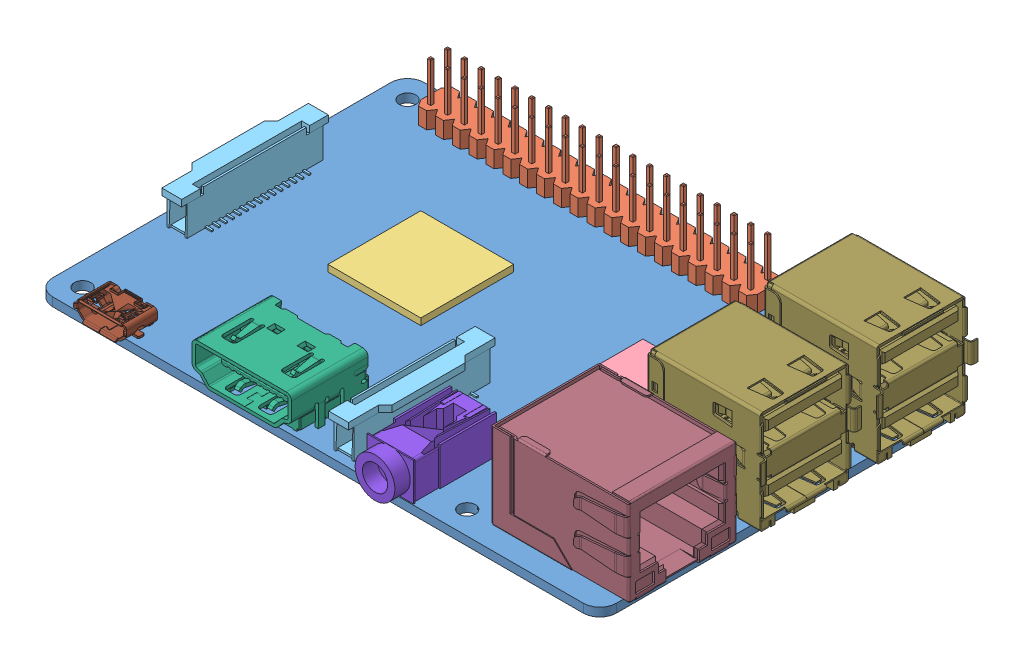
SolidWorks assembly User Library-RaspberryPi2 STEP214, configuration Default. Lengths in mm.
Overall size (91.42 27.08 66.27).
15 component instances, 13 part files, 0 mates.
Components (placement in the parent):
- User Library-RaspberryPi2 STEP214_Mainboard2-1: User Library-RaspberryPi2 STEP214_Mainboard2 [Default] at origin size (85 1.3 56)
- User Library-RaspberryPi2 STEP214_GPIO-1: User Library-RaspberryPi2 STEP214_GPIO [Default] at (-11.37 0 -24.5) x (0 0 1) z (-1 0 0) size (5 11.5 50.8)
- User Library-RaspberryPi2 STEP214_Processor-1: User Library-RaspberryPi2 STEP214_Processor [Default] at (-15.5 0 -3) x (0 0 1) z (-1 0 0) size (14 1 14)
- User Library-RaspberryPi2 STEP214_GPU-1: User Library-RaspberryPi2 STEP214_GPU [Default] at (15.25 0 -5.75) x (0 0 1) z (-1 0 0) size (9.1 1 9.1)
- User Library-RaspberryPi2 STEP214_CameraAssembly-1: User Library-RaspberryPi2 STEP214_CameraAssembly [Default] at (10.0885 -2.9159 16.55) x (-1 0 0) z (0 0 -1) size (6.09 6.17 23.84)
- User Library-RaspberryPi2 STEP214_CameraAssembly-2: User Library-RaspberryPi2 STEP214_CameraAssembly [Default] at (-46.3885 -2.9159 0) size (6.09 6.17 23.84)
- User Library-RaspberryPi2 STEP214_HDMI-1: User Library-RaspberryPi2 STEP214_HDMI [Default] at (-10.2 0.27 29.3) size (15 8.38 12.15)
- User Library-RaspberryPi2 STEP214_RAM-1: User Library-RaspberryPi2 STEP214_RAM [Default] at (0.5 -2.3 -6) x (0 0 1) z (-1 0 0) size (12 1 12)
- User Library-RaspberryPi2 STEP214_Audio-1: User Library-RaspberryPi2 STEP214_Audio [Default] at (10.9 0.15 21.75) size (7 6 14.8)
- User Library-RaspberryPi2 STEP214_MicroSDSocket-1: User Library-RaspberryPi2 STEP214_MicroSDSocket [Default] at (-34.5 -1.3 -0.7) x (0 0 -1) z (-1 0 0) size (13 1.3 14)
- User Library-RaspberryPi2 STEP214_MicroSD-1: User Library-RaspberryPi2 STEP214_MicroSD [Default] at (-37 -2.3 0.1) x (0 0 1) z (-1 0 0) size (11.29 1 15)
- User Library-RaspberryPi2 STEP214_micro USB2-1: User Library-RaspberryPi2 STEP214_micro USB2 [Default] at (-17.2704 -5.0969 44.9026) size (22.78 22.78 22.78)
- User Library-RaspberryPi2 STEP214_usb double-1: User Library-RaspberryPi2 STEP214_usb double [Default] at (30.38 -0.09 -18.85) x (0 0 -1) z (1 0 0) size (15.6 18.75 17.92)
- User Library-RaspberryPi2 STEP214_usb double-2: User Library-RaspberryPi2 STEP214_usb double [Default] at (30.38 -0.09 -1.25) x (0 0 -1) z (1 0 0) size (15.6 18.75 17.92)
- User Library-RaspberryPi2 STEP214_RJ45-LED-1: User Library-RaspberryPi2 STEP214_RJ45-LED [Default] at (34.11 7.4 17.348) x (1 0 0) z (0 -1 0) size (23.41 18.34 17.45)
